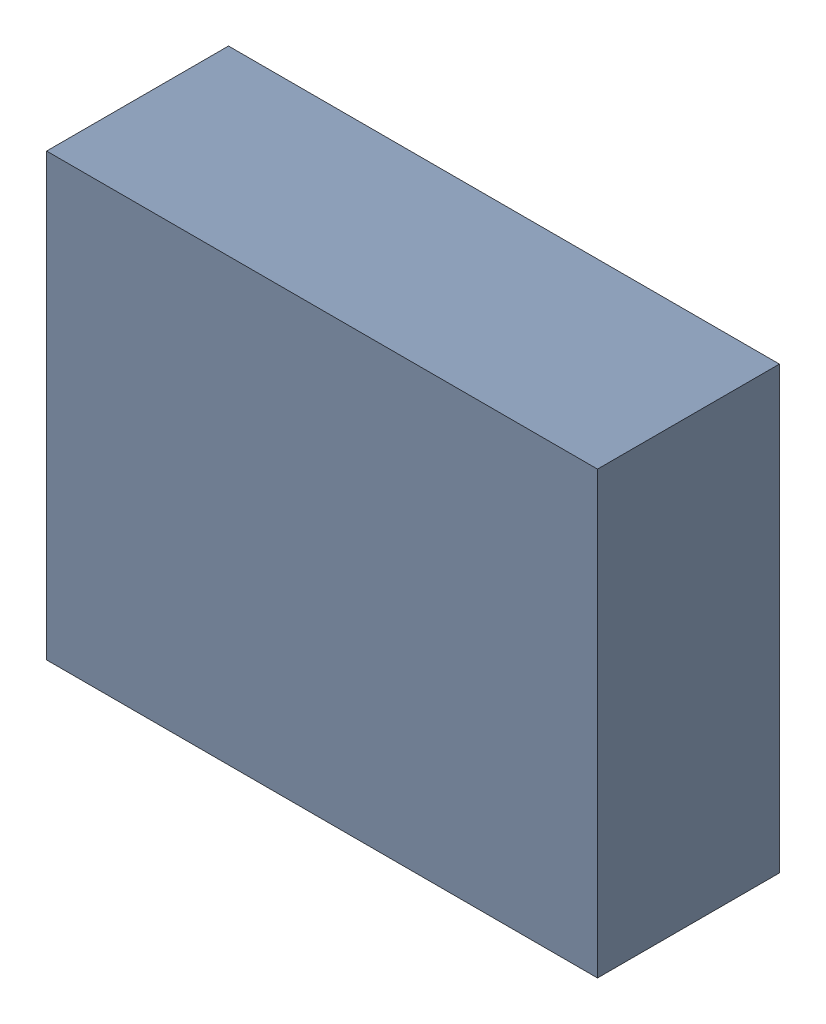
SolidWorks assembly USB23_U2, configuration Default. Lengths in mm.
Overall size (5 4 1.65).
2 component instances, 1 part files, 0 mates.
Components (placement in the parent):
- 402662672-1: 402662672 [Default] at (156.845 54.61 -2.8544) size (5 4 1.65)
  - Extruded_31-1: Extruded_31 [Default] at origin size (5 4 1.65)
